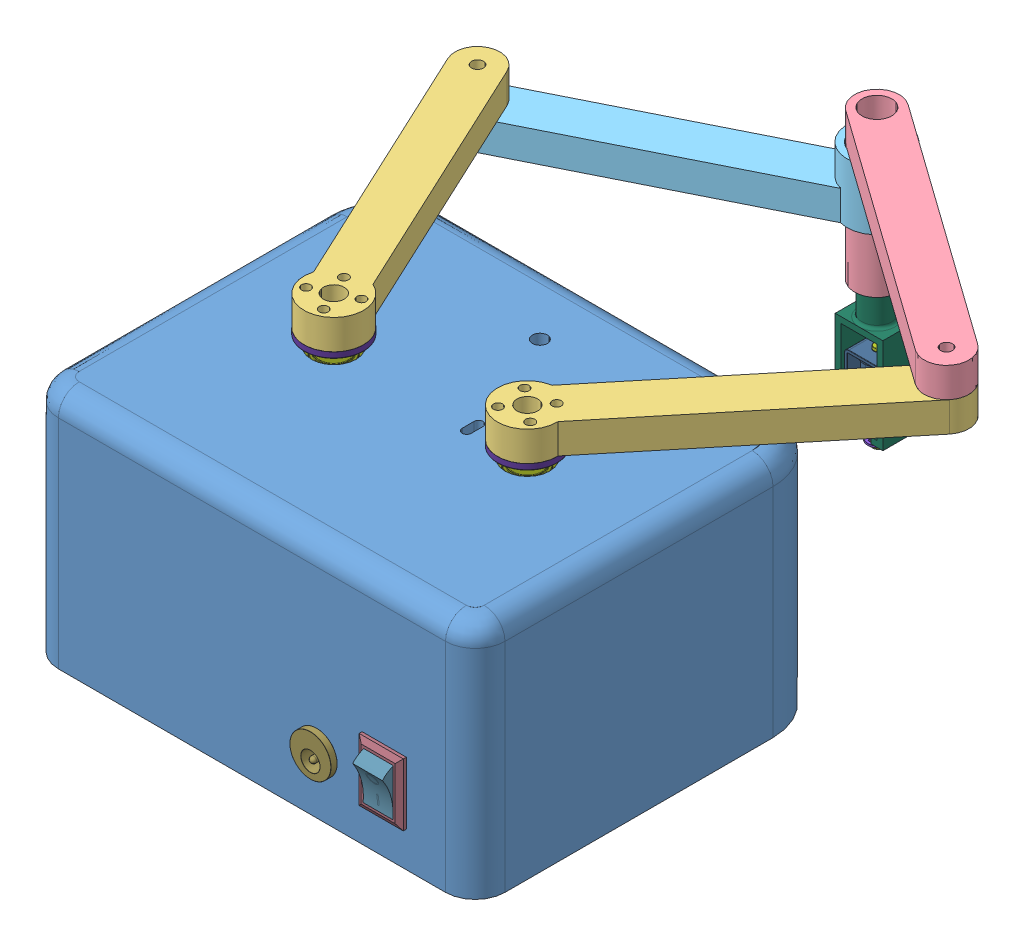
SolidWorks assembly AssemV2, configuration Default. Lengths in mm.
Overall size (195.64 105.5 215.11).
23 component instances, 17 part files, 38 mates.
Components (placement in the parent):
- base-1: base [Default] at (106.5 27.1593 136.4053) size (150 80 120)
- disk-1: disk [Default] at (106.5 27.1593 136.4053) size (145 3 115)
- bicep-1: bicep [Default] at (139 112.6593 136.4053) x (0.635833 0 -0.771827) z (0.771827 0 0.635833) size (117.5 10 20)
- bicep-2: bicep [Default] at (74 112.6593 136.4053) x (-0.423364 0 -0.90596) z (0.90596 0 -0.423364) size (117.5 10 20)
- forecep_right-1: forecep_right [Default] at (121.1522 122.6593 1.1798) x (0.814311 0 0.580428) z (-0.580428 0 0.814311) size (117.49 50 17.49)
- forecep_left-1: forecep_left [Default] at (31.6636 102.6593 45.8093) x (0.894886 0 -0.446295) z (0.446295 0 0.894886) size (117.5 20 20)
- Keyestudio CNC Shield Arduino Nano-1: Keyestudio CNC Shield Arduino Nano [Default] at (71.875 70.4093 186.9053) x (-1 0 0) z (0 -1 0) size (71.75 12.6 58.5)
- Solenoid.STEP-1: Solenoid.STEP [Default] at (127.1522 41.7973 6.1798) x (0 1 0) z (0 0 -1) size (29 12 11)
  - Shaft Assem.STEP-1: Shaft Assem.STEP [Default] at (2.5 -6 5.5) x (0 0.575247 0.81798) z (1 0 0) size (7.1 6.75 29)
    - Shaft.STEP-1: Shaft.STEP [Default] at origin size (4 4 29)
    - Circlip.STEP-1: Circlip.STEP [Default] at (0 0 -8.45) size (7.1 5.79 0.6)
    - Spring.STEP-1: Spring.STEP [Default] at (0 0 -2.3) x (-1 0 0) z (0 0 -1) size (6.28 6.48 5.72)
  - Shell.STEP-1: Shell.STEP [Default] at origin size (20.5 12 11)
- ARDUINO NANO-1: ARDUINO NANO [Default] at (63.25 76.7893 172.6553) x (0 1 0) z (-1 0 0) size (18 19.4 44.8)
- DC Coax Panel Mount Power Jack (PN 601)-1: DC Coax Panel Mount Power Jack (PN 601) [default] at (128.2373 46.3921 196.4053) size (13.8 13.8 18.1)
- Switch Montaj-1: Switch Montaj [Varsayılan] at (150.8539 50.7648 162.2053) x (0 1 0) z (0 0 1) size (21.23 14.85 25.41)
  - Switch-1: Switch [Varsayılan] at (-10.7432 -5.856 23) size (21.23 14.85 21.45)
  - Switch Açma Kapama-2: Switch Açma Kapama [Varsayılan] at (-0.3897 4.944 31.6284) x (0.965926 0 0.258819) z (0 -1 0) size (16.31 8 10)
- solenoidHolder-1: solenoidHolder [Default] at (121.1522 55.7973 1.1798) x (-1 0 0) z (0 0 -1) size (16 67 13.5)
- MG995.step-1: MG995.step [Default] at (139 66.1593 126.4053) x (0 0 1) z (0 1 0) size (55.5 20 44.5)
- MG995.step-2: MG995.step [Default] at (74 66.1593 126.4053) x (0 0 1) z (0 1 0) size (55.5 20 44.5)
- MG955 horn-1: MG955 horn [Default] at (139 110.6593 136.4053) size (20 4.5 20)
- MG955 horn-2: MG955 horn [Default] at (74 110.6593 136.4053) x (0.99993 0 -0.011854) z (0.011854 0 0.99993) size (20 4.5 20)
Mates (geometry in assembly coordinates):
- Concentric21: concentric aligned: cylinder of bicep-1 through (202.5833 122.6593 59.2227) axis (0 -1 0) radius 2; cylinder of forecep_right-1 through (202.5833 132.6593 59.2227) axis (0 -1 0) radius 2
- Coincident14: coincident anti-aligned: plane of bicep-2 through (74 112.6593 136.4053) normal (0 -1 0); plane of forecep_left-1 through (31.6636 112.6593 45.8093) normal (0 1 0)
- Concentric23: concentric aligned: cylinder of bicep-2 through (31.6636 122.6593 45.8093) axis (0 -1 0) radius 2; cylinder of forecep_left-1 through (31.6636 112.6593 45.8093) axis (0 -1 0) radius 2
- Coincident31: coincident anti-aligned: plane of bicep-1 through (139 122.6593 136.4053) normal (0 1 0); plane of forecep_right-1 through (121.1522 122.6593 1.1798) normal (0 -1 0)
- Concentric26: concentric aligned: cylinder of forecep_right-1 through (121.1522 132.6593 1.1798) axis (0 1 0) radius 7.5; cylinder of forecep_left-1 through (121.1522 102.6583 1.1798) axis (0 1 0) radius 7.75
- Coincident34: coincident anti-aligned: plane of base-1 through (34 107.1593 76.4053) normal (1 0 0); plane of disk-1 through (34 30.1593 78.9053) normal (-1 0 0)
- Coincident35: coincident anti-aligned: plane of Keyestudio CNC Shield Arduino Nano-1 through (71.875 70.4093 176.8053) normal (0 0 -1); plane of ARDUINO NANO-1 through (63.25 76.7893 176.8053) normal (0 0 1)
- Width1: width aligned: plane of ARDUINO NANO-1 through (82.3 83.1593 176.8053) normal (1 0 0); plane of Keyestudio CNC Shield Arduino Nano-1 through (44.2 83.1593 176.8053) normal (-1 0 0); plane of ARDUINO NANO-1 through (82.5 85.6593 176.8053) normal (1 0 0); plane of Keyestudio CNC Shield Arduino Nano-1 through (44 85.6593 176.8053) normal (-1 0 0)
- Width2: width anti-aligned: plane of ARDUINO NANO-1 through (44.2 85.6593 176.8053) normal (0 1 0); plane of Keyestudio CNC Shield Arduino Nano-1 through (44.2 83.1593 176.8053) normal (0 -1 0); plane of ARDUINO NANO-1 through (82.5 83.1593 176.8053) normal (0 -1 0); plane of Keyestudio CNC Shield Arduino Nano-1 through (82.5 85.6593 176.8053) normal (0 1 0)
- Coincident38: coincident anti-aligned: plane of base-1 through (36 97.1593 186.9053) normal (0 0 -1); plane of Keyestudio CNC Shield Arduino Nano-1 through (71.875 70.4093 186.9053) normal (0 0 1)
- Coincident39: coincident anti-aligned: plane of base-1 through (36 97.1593 184.4053) normal (1 0 0); plane of Keyestudio CNC Shield Arduino Nano-1 through (36 41.1593 185.3053) normal (-1 0 0)
- Coincident42: coincident anti-aligned: plane of base-1 through (106.5 97.1593 136.4053) normal (0 -1 0); plane of Keyestudio CNC Shield Arduino Nano-1 through (44 97.1593 182.8053) normal (0 1 0)
- Concentric29: concentric anti-aligned: cylinder of base-1 through (128.2373 46.3921 76.4043) axis (0 0 1) radius 6.15; cylinder of DC Coax Panel Mount Power Jack (PN 601)-1 through (128.2373 46.3921 198.5053) axis (0 0 -1) radius 6.9
- Coincident43: coincident anti-aligned: plane of base-1 through (31.5 107.1593 196.4053) normal (0 0 1); plane of DC Coax Panel Mount Power Jack (PN 601)-1 through (128.2373 46.3921 196.4053) normal (0 0 -1)
- Width3: width anti-aligned: plane of Switch Montaj-1/Switch-1 through (145.1099 40.0217 187.4053) normal (-1 0 0); plane of Switch Montaj-1/Switch-1 through (156.7099 40.0217 187.4053) normal (1 0 0); plane of base-1 through (144.1599 59.4217 76.4043) normal (1 0 0); plane of base-1 through (157.6599 59.4217 76.4043) normal (-1 0 0)
- Width4: width anti-aligned: plane of Switch Montaj-1/Switch-1 through (145.1099 58.6217 196.4053) normal (0 1 0); plane of Switch Montaj-1/Switch-1 through (145.1099 40.2217 196.4053) normal (0 -1 0); plane of base-1 through (144.1599 59.4217 76.4043) normal (0 -1 0); plane of base-1 through (144.1599 39.4217 76.4043) normal (0 1 0)
- Coincident44: coincident anti-aligned: plane of base-1 through (31.5 107.1593 196.4053) normal (0 0 1); plane of Switch Montaj-1/Switch-1 through (156.7099 40.0217 196.4053) normal (0 0 -1)
- Coincident45: coincident anti-aligned: plane of base-1 through (159 30.1593 98.9053) normal (0 -1 0); plane of disk-1 through (106.5 30.1593 136.4053) normal (0 1 0)
- Coincident46: coincident anti-aligned: plane of base-1 through (31.5 107.1593 193.9053) normal (0 0 -1); plane of disk-1 through (34 30.1593 193.9053) normal (0 0 1)
- Coincident47: coincident anti-aligned: plane of Solenoid.STEP-1/Shell.STEP-1 through (115.1522 62.2973 -4.8202) normal (-1 0 0); plane of solenoidHolder-1 through (115.1522 41.7973 -4.8202) normal (1 0 0)
- Coincident48: coincident anti-aligned: plane of Solenoid.STEP-1/Shell.STEP-1 through (116.1522 41.7973 -4.8202) normal (0 -1 0); plane of solenoidHolder-1 through (117.1522 41.7973 -4.8202) normal (0 1 0)
- Coincident49: coincident anti-aligned: plane of Solenoid.STEP-1/Shell.STEP-1 through (127.1522 41.7973 -4.8202) normal (0 0 -1); plane of solenoidHolder-1 through (121.1522 55.7973 -4.8202) normal (0 0 1)
- Concentric30: concentric anti-aligned: cylinder of forecep_right-1 through (121.1522 82.6583 1.1798) axis (0 1 0) radius 5; cylinder of solenoidHolder-1 through (121.1522 106.7973 1.1798) axis (0 -1 0) radius 5
- Parallel1: parallel aligned: plane of base-1 through (31.5 107.1593 76.4053) normal (0 0 -1); plane of solenoidHolder-1 through (121.1522 55.7973 -6.3202) normal (0 0 -1)
- Concentric31: concentric anti-aligned: cylinder of base-1 through (134 95.1593 102.4053) axis (0 1 0) radius 1.5; cylinder of MG995.step-1 through (134 95.1593 102.4053) axis (0 -1 0) radius 2
- Concentric32: concentric anti-aligned: cylinder of base-1 through (144 95.1593 150.4053) axis (0 1 0) radius 1.5; cylinder of MG995.step-1 through (144 95.1593 150.4053) axis (0 -1 0) radius 2
- Concentric33: concentric anti-aligned: cylinder of base-1 through (79 95.1593 150.4053) axis (0 1 0) radius 1.5; cylinder of MG995.step-2 through (79 95.1593 150.4053) axis (0 -1 0) radius 2
- Concentric34: concentric anti-aligned: cylinder of base-1 through (69 95.1593 102.4053) axis (0 1 0) radius 1.5; cylinder of MG995.step-2 through (69 95.1593 102.4053) axis (0 -1 0) radius 2
- Coincident50: coincident aligned: plane of MG995.step-1 through (139 93.1593 126.4053) normal (0 -1 0); plane of MG995.step-2 through (74 93.1593 126.4053) normal (0 -1 0)
- Coincident51: coincident anti-aligned: plane of base-1 through (106.5 95.1593 136.4053) normal (0 -1 0); plane of MG995.step-2 through (74 95.1593 126.4053) normal (0 1 0)
- Concentric35: concentric anti-aligned: circle of MG995.step-1; circle of MG955 horn-1
- Concentric36: concentric anti-aligned: circle of MG995.step-2; circle of MG955 horn-2
- Concentric37: concentric aligned: cylinder of bicep-1 through (139 112.6593 136.4053) axis (0 1 0) radius 3.5; cylinder of MG955 horn-1 through (139 108.1593 136.4053) axis (0 1 0) radius 1
- Coincident52: coincident anti-aligned: plane of bicep-1 through (139 112.6593 136.4053) normal (0 -1 0); plane of MG955 horn-1 through (139 112.6593 136.4053) normal (0 1 0)
- Concentric38: concentric aligned: cylinder of bicep-2 through (74 112.6593 136.4053) axis (0 1 0) radius 3.5; cylinder of MG955 horn-2 through (74 108.1593 136.4053) axis (0 1 0) radius 1
- Coincident53: coincident anti-aligned: plane of bicep-2 through (74 112.6593 136.4053) normal (0 -1 0); plane of MG955 horn-2 through (74 112.6593 136.4053) normal (0 1 0)
- Coincident54: coincident anti-aligned: plane of forecep_right-1 through (121.1522 122.6593 1.1798) normal (0 -1 0); plane of forecep_left-1 through (121.1522 122.6593 1.1798) normal (0 1 0)
- Coincident55: coincident anti-aligned: plane of MG995.step-1 through (139 110.6593 136.4053) normal (0 1 0); plane of MG955 horn-1 through (139 110.6593 136.4053) normal (0 -1 0)
